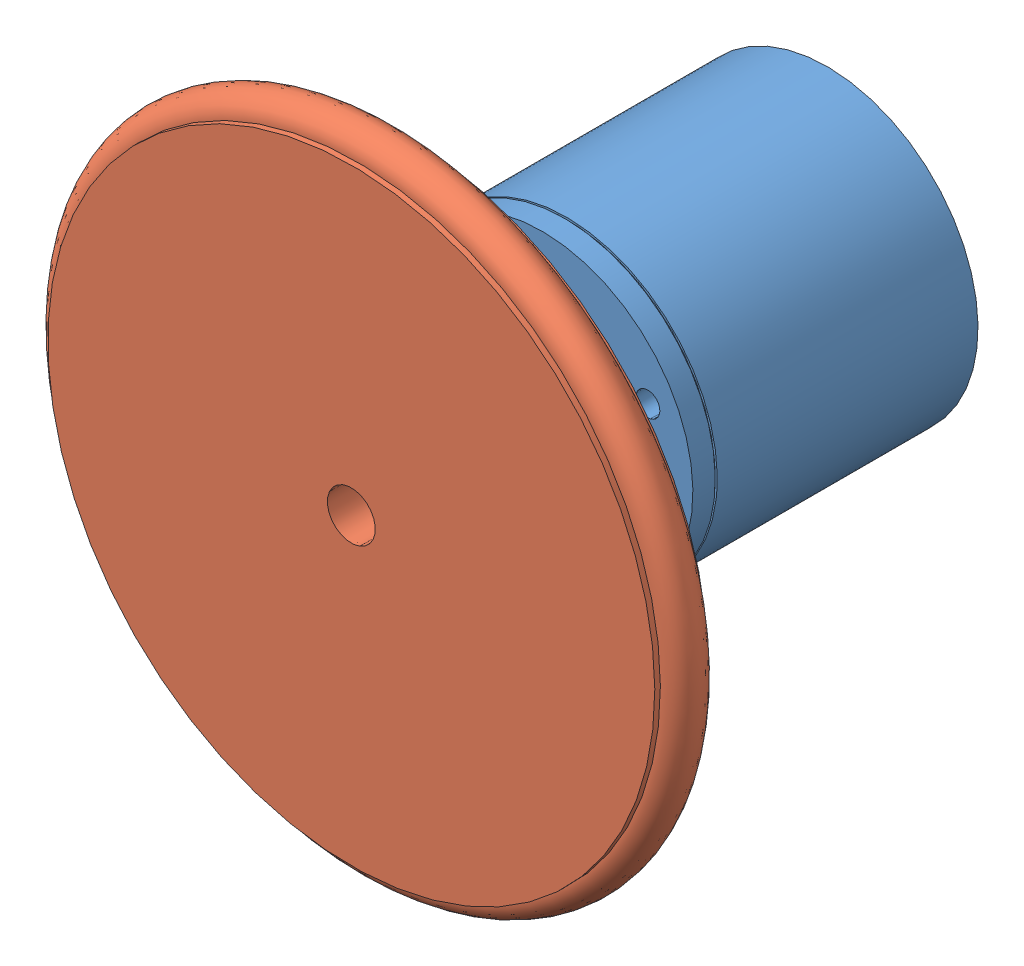
SolidWorks assembly ASSEMBLAGE ENCODERUR, configuration Default. Lengths in mm.
Overall size (104.33 104.33 59.57).
2 component instances, 2 part files, 4 mates.
Components (placement in the parent):
- Encodeur TR-1: Encodeur TR [Défaut] at (54.6939 14.5727 44.0041) x (-0.998749 0.05 0) z (0 0 1) size (37.8 37.8 52.6)
- Roue Encodeur-1: Roue Encodeur [Défaut] at (54.6939 14.5727 103.4741) x (0 0 -1) z (0.935978 0.35206 0) size (16.57 81 81)
Mates (geometry in assembly coordinates):
- Concentric7: concentric aligned: cylinder of Encodeur TR-1 through (54.6939 14.5727 96.5041) axis (0 0 -1) radius 3.05; cylinder of Roue Encodeur-1 through (54.6939 14.5727 103.4741) axis (0 0 -1) radius 3
- Coincident6: coincident anti-aligned: plane of Encodeur TR-1 through (54.6939 14.5727 86.9041) normal (0 0 1); plane of Roue Encodeur-1 through (54.6939 14.5727 86.9041) normal (0 0 -1)
- Concentric14: concentric: cylinder of Encodeur TR-1 through (54.6939 14.5727 -96.5041) axis (0 0 -1) radius 3.05; cylinder of Roue Encodeur-1 through (54.6939 14.5727 -103.4741) axis (0 0 1) radius 3
- Coincident12: coincident: plane of Encodeur TR-1 through (54.6939 14.5727 -86.9041) normal (0 0 -1); plane of Roue Encodeur-1 through (54.6939 14.5727 -86.9041) normal (0 0 1)
